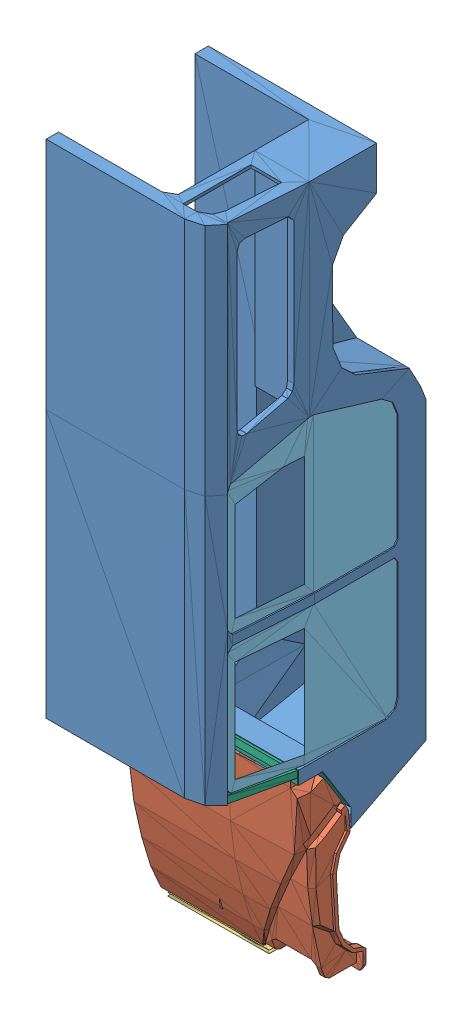
SolidWorks assembly сборка кузова, configuration Default. Lengths in mm.
Overall size (46.98 196.36 58.34).
6 component instances, 6 part files, 0 mates.
Components (placement in the parent):
- кузов3_1-1: кузов3_1 [Default] at (-17.441 -20.6919 0.7155) size (46.47 160.35 58.34)
- кузов3_2-1: кузов3_2 [Default] at (-44.6881 -7.9821 -7.3138) size (46.98 52.77 19.92)
- кузов3_3-1: кузов3_3 [Default] at (-43.2786 -9.27 -8.197) size (27.9 3.47 10.42)
- кузов3_4-1: кузов3_4 [Default] at (-91.055 -5.8609 1.8953) size (19.56 47.38 20.89)
- кузов3_5-1: кузов3_5 [Default] at (-64.3752 -20.701 0.5604) size (3.11 82.96 45.77)
- кузов3_6-1: кузов3_6 [Default] at (-90.9679 -20.584 0.9283) size (46.47 18.42 35.02)
